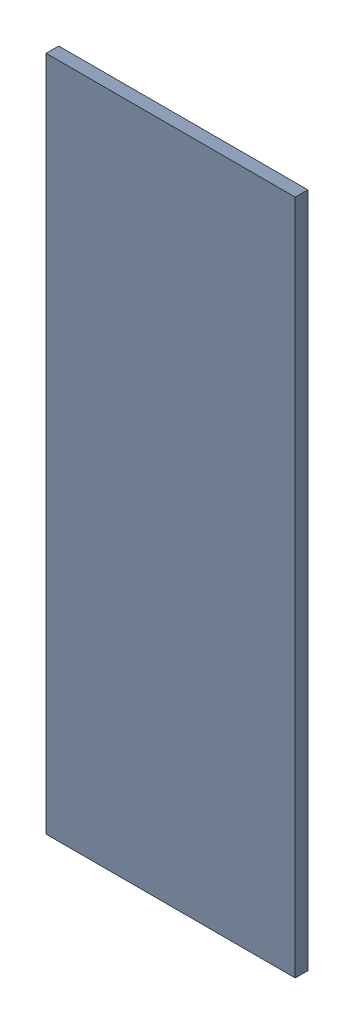
SolidWorks assembly Pad RAK4600-17(21.225mm,8.691mm) on Top Layer, configuration Predeterminado. Lengths in mm.
Overall size (0.7 1.9 0.04).
2 component instances, 1 part files, 0 mates.
Components (placement in the parent):
- Pad RAK4600-17(21.225mm,8.691mm) on Top Layer-1-1: Pad RAK4600-17(21.225mm,8.691mm) on Top Layer-1 [Predeterminado] at (-68.317 -44.187 -0.0457) size (0.7 1.9 0.04)
  - Pad RAK4600-17(21.225mm,8.691mm) on Top Layer-Part-1-1: Pad RAK4600-17(21.225mm,8.691mm) on Top Layer-Part-1 [Predeterminado] at origin size (0.7 1.9 0.04)
